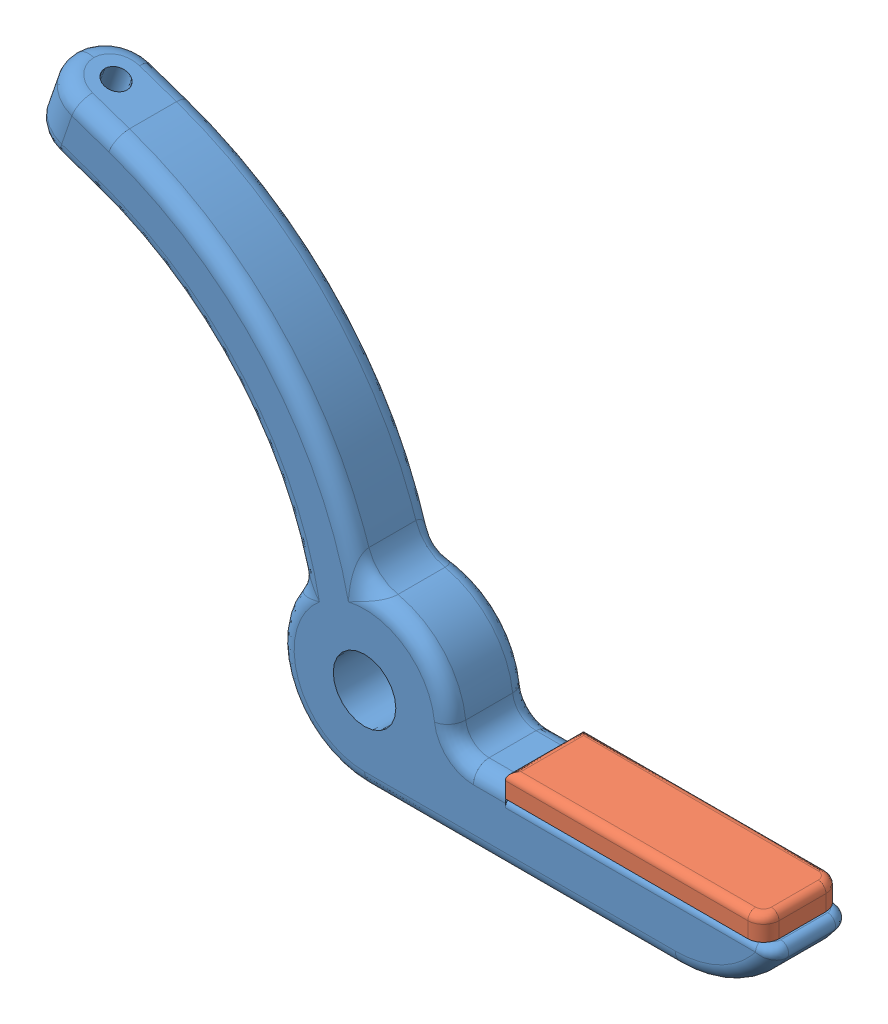
SolidWorks assembly Assieme_ELEMETO_PRESA_TRAZ, configuration Default. Lengths in mm.
Overall size (95.6 59.87 10.78).
3 component instances, 3 part files, 5 mates.
Components (placement in the parent):
- ELEMENTO_PRESA_TRAZ-1: ELEMENTO_PRESA_TRAZ [Default] at (42.1638 -16.4858 76.7684) size (95.6 59.87 10.56)
- MATERIALE_SOFT_3D-2: MATERIALE_SOFT_3D [Default] at (60.1638 -16.4858 83.7684) size (33 5 10)
- BOCCOLA_RSONLINE-1: BOCCOLA_RSONLINE [Default] at (42.1638 -16.4858 83.2684) x (0 0 1) z (-0.166887 -0.985976 0) size (4 12 12)
Mates (geometry in assembly coordinates):
- Coincidente1: coincident anti-aligned: plane of ELEMENTO_PRESA_TRAZ-1 through (60.1638 -21.4858 93.7684) normal (0 1 0); plane of MATERIALE_SOFT_3D-2 through (60.1638 -21.4858 93.7684) normal (0 -1 0)
- Coincidente2: coincident aligned: plane of ELEMENTO_PRESA_TRAZ-1 through (-57.8362 -28.4858 83.7684) normal (0 0 -1); plane of MATERIALE_SOFT_3D-2 through (60.1638 -16.4858 83.7684) normal (0 0 -1)
- Coincidente3: coincident anti-aligned: plane of ELEMENTO_PRESA_TRAZ-1 through (60.1638 -17.9858 93.7684) normal (1 0 0); plane of MATERIALE_SOFT_3D-2 through (60.1638 -16.4858 93.7684) normal (-1 0 0)
- Concentrico1: concentric anti-aligned: cylinder of ELEMENTO_PRESA_TRAZ-1 through (42.1638 -16.4858 93.7684) axis (0 0 -1) radius 4.25; cylinder of BOCCOLA_RSONLINE-1 through (42.1638 -16.4858 83.2684) axis (0 0 1) radius 4
- Coincidente4: coincident anti-aligned: plane of ELEMENTO_PRESA_TRAZ-1 through (42.1638 -16.4858 84.2684) normal (0 0 -1); plane of BOCCOLA_RSONLINE-1 through (38.2199 -15.8182 84.2684) normal (0 0 1)
